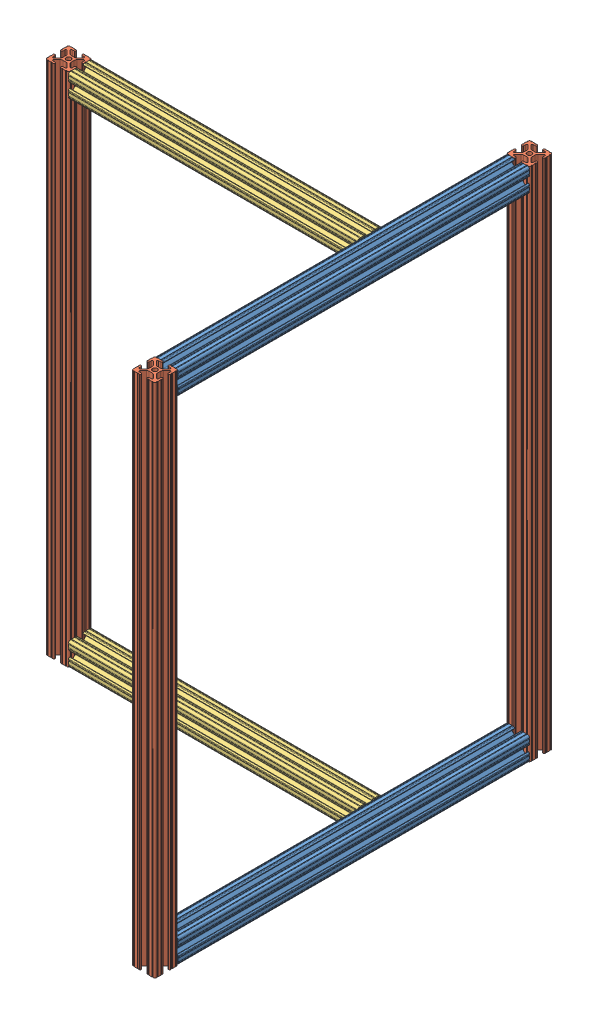
SolidWorks assembly Frame Assembly, configuration Default. Lengths in mm.
Overall size (365.51 561.34 433.07).
7 component instances, 3 part files, 18 mates.
Components (placement in the parent):
- T Slot Frame 15.05 in-1: T Slot Frame 15.05 in [47065T209] at (40.7597 171.6011 479.8247) size (25.4 25.4 382.27)
- T Slot Frame 22.1 in-1: T Slot Frame 22.1 in [47065T209] at (40.7597 415.4411 569.9947) x (-1 0 0) z (0 -1 0) size (25.4 25.4 561.34)
- T Slot Frame 22.1 in-2: T Slot Frame 22.1 in [47065T209] at (40.7597 415.4411 162.3247) x (-1 0 0) z (0 -1 0) size (25.4 25.4 561.34)
- T Slot Frame 15.05 in-2: T Slot Frame 15.05 in [47065T209] at (40.7597 707.5411 479.8247) size (25.4 25.4 382.27)
- T Slot Frame 12.39 in-1: T Slot Frame 12.39 in [47065T209] at (18.1537 171.6011 323.8687) x (0 0 -1) z (1 0 0) size (25.4 25.4 314.71)
- T Slot Frame 12.39 in-2: T Slot Frame 12.39 in [47065T209] at (18.1537 707.5411 323.8687) x (0 0 -1) z (1 0 0) size (25.4 25.4 314.71)
- T Slot Frame 22.1 in-3: T Slot Frame 22.1 in [47065T209] at (-299.3463 415.4411 323.8687) x (1 0 0) z (0 -1 0) size (25.4 25.4 561.34)
Mates (geometry in assembly coordinates):
- Coincident1: coincident anti-aligned: plane of T Slot Frame 1.5FT-1 through (40.7597 171.6011 557.2947) normal (0 0 1); plane of T Slot Frame 22.1 in-1 through (47.0929 110.6411 557.2947) normal (0 0 -1)
- Coincident2: coincident aligned: plane of T Slot Frame 1.5FT-1 through (31.2093 158.9011 784.6247) normal (0 -1 0); plane of T Slot Frame 22.1 in-1 through (40.7597 158.9011 569.9947) normal (0 -1 0)
- Coincident3: coincident aligned: plane of T Slot Frame 1.5FT-1 through (28.0597 165.268 784.6247) normal (-1 0 0); plane of T Slot Frame 22.1 in-1 through (28.0597 110.6411 563.6616) normal (-1 0 0)
- Coincident4: coincident anti-aligned: plane of T Slot Frame 1.5FT-1 through (34.3433 162.1912 175.0247) normal (0 0 -1); plane of T Slot Frame 22.1 in-2 through (34.4266 110.6411 175.0247) normal (0 0 1)
- Coincident5: coincident aligned: plane of T Slot Frame 1.5FT-1 through (28.0597 165.268 784.6247) normal (-1 0 0); plane of T Slot Frame 22.1 in-2 through (28.0597 110.6411 171.8751) normal (-1 0 0)
- Coincident6: coincident aligned: plane of T Slot Frame 1.5FT-1 through (31.2093 158.9011 784.6247) normal (0 -1 0); plane of T Slot Frame 22.1 in-2 through (40.7597 158.9011 162.3247) normal (0 -1 0)
- Coincident7: coincident anti-aligned: plane of T Slot Frame 22.1 in-1 through (31.2093 110.6411 557.2947) normal (0 0 -1); plane of T Slot Frame 1.5FT-2 through (40.7597 707.5411 557.2947) normal (0 0 1)
- Coincident8: coincident aligned: plane of T Slot Frame 22.1 in-1 through (28.0597 110.6411 579.5451) normal (-1 0 0); plane of T Slot Frame 1.5FT-2 through (28.0597 701.208 784.6247) normal (-1 0 0)
- Coincident9: coincident aligned: plane of T Slot Frame 22.1 in-1 through (47.1761 720.2411 579.4045) normal (0 1 0); plane of T Slot Frame 1.5FT-2 through (34.4266 720.2411 784.6247) normal (0 1 0)
- Coincident10: coincident anti-aligned: plane of T Slot Frame 1.5FT-1 through (28.0597 181.1515 784.6247) normal (-1 0 0); plane of T Slot Frame 14.39 in-1 through (28.0597 171.6011 323.8687) normal (1 0 0)
- Coincident11: coincident aligned: plane of T Slot Frame 1.5FT-1 through (31.2093 158.9011 784.6247) normal (0 -1 0); plane of T Slot Frame 14.39 in-1 through (322.9537 158.9011 333.4191) normal (0 -1 0)
- Distance1: distance = 161.544 mm aligned: plane of T Slot Frame 14.39 in-1 through (322.9537 177.9341 311.1687) normal (0 0 -1); plane of T Slot Frame 22.1 in-2 through (31.2093 110.6411 149.6247) normal (0 0 -1)
- Coincident13: coincident anti-aligned: plane of T Slot Frame 1.5FT-2 through (28.0597 701.208 784.6247) normal (-1 0 0); plane of T Slot Frame 14.39 in-2 through (28.0597 707.5411 323.8687) normal (1 0 0)
- Coincident14: coincident aligned: plane of T Slot Frame 1.5FT-2 through (31.2093 694.8411 784.6247) normal (0 -1 0); plane of T Slot Frame 14.39 in-2 through (322.9537 694.8411 317.5355) normal (0 -1 0)
- Distance2: distance = 161.544 mm aligned: plane of T Slot Frame 22.1 in-2 through (31.2093 110.6411 149.6247) normal (0 0 -1); plane of T Slot Frame 14.39 in-2 through (322.9537 697.9907 311.1687) normal (0 0 -1)
- Coincident16: coincident aligned: plane of T Slot Frame 14.39 in-1 through (322.9537 158.9011 333.4191) normal (0 -1 0); plane of T Slot Frame 22.1 in-3 through (-299.3463 158.9011 323.8687) normal (0 -1 0)
- Coincident17: coincident aligned: plane of T Slot Frame 14.39 in-1 through (322.9537 165.268 336.5687) normal (0 0 1); plane of T Slot Frame 22.1 in-3 through (-289.7958 110.6411 336.5687) normal (0 0 1)
- Coincident18: coincident anti-aligned: plane of T Slot Frame 14.39 in-1 through (-286.6463 162.1912 330.2851) normal (-1 0 0); plane of T Slot Frame 22.1 in-3 through (-286.6463 110.6411 314.3183) normal (1 0 0)
